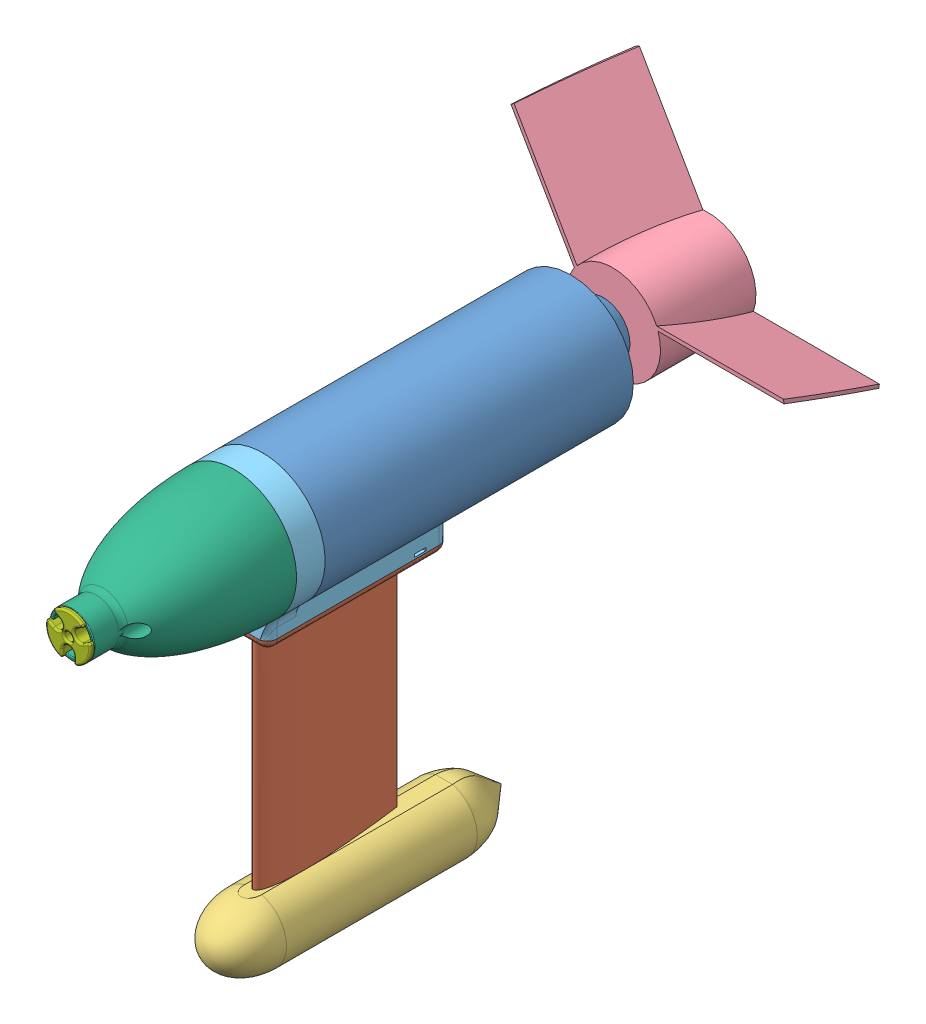
SolidWorks assembly reverse cat assembly, configuration Default. Lengths in mm.
Overall size (143.38 280.15 343.66).
7 component instances, 7 part files, 22 mates.
Components (placement in the parent):
- Flipsky 65161 Motor-2: Flipsky 65161 Motor [Default] at (22.7291 38 -117.7677) x (0.707107 0.707107 0) z (0 0 -1) size (65.5 65.5 241.5)
- mast - naca 0012-1: mast - naca 0012 [Default] at (22.7291 -62.5 -32.0177) x (0 0 -1) z (-1 0 0) size (95.94 125 35)
- bulb-1: bulb [Default] at (22.7291 -141.9115 -82.0177) size (35.27 35.28 155)
- prop-1: prop [Default] at (22.7291 38 -220.5177) x (1 0 0) z (0 1 0) size (143.38 50 164.92)
- reverse cat-2: reverse cat [Default] at (22.7291 38 -29.5177) x (-1 0 0) z (0 -1 0) size (65.5 95 71.11)
- nose cone-1: nose cone [Default] at (22.7291 38 -22.0177) x (0 0 1) z (-1 0 0) size (85 69.42 68.43)
- nose plug-1: nose plug [Default] at (22.7291 38 64.9823) x (1 0 0) z (0 1 0) size (23.52 14.81 22.73)
Mates (geometry in assembly coordinates):
- Coincident1: coincident: plane of ? through (-60605.8469 -37519.4359 -15) normal (0 0 -1); plane of Flipsky 65161 Motor-2 through (-28.2165 86.462 -15) normal (0 0 1)
- Coincident2: coincident: plane of mast - naca 0012-1 through (22.924 -125 -32.0449) normal (0 -1 0); plane of bulb-1 through (18.2291 -125 -132.0177) normal (0 1 0)
- Concentric4: concentric: circle of bulb-1; circle of mast - naca 0012-1
- Distance1: distance = 8 mm: plane of Flipsky 65161 Motor-2 through (22.7291 38 -278.5177) normal (0 0 -1); plane of prop-1 through (22.7291 38 -270.5177) normal (0 0 -1)
- Concentric6: concentric: circle of Flipsky 65161 Motor-2; circle of prop-1
- Coincident4: coincident: plane of ? through (-60605.8469 -37519.4359 0) normal (0 0 1); plane of assembly through (0 0 0) normal (0 0 1)
- Concentric11: concentric: circle of bulb-1; circle of mast - naca 0012-1
- Coincident7: coincident: plane of Flipsky 65161 Motor-2 through (22.7291 38 -37.0177) normal (0 0 1); plane of reverse cat-2 through (22.7291 38 -37.0177) normal (0 0 -1)
- Concentric12: concentric: circle of Flipsky 65161 Motor-2; circle of reverse cat-2
- Coincident8: coincident: plane of mast - naca 0012-1 through (22.924 0 -32.0449) normal (0 1 0); plane of reverse cat-2 through (10.2291 0 -27.0177) normal (0 -1 0)
- Concentric13: concentric: circle of mast - naca 0012-1; circle of reverse cat-2
- Concentric14: concentric: circle of mast - naca 0012-1; circle of reverse cat-2
- Concentric15: concentric: circle of Flipsky 65161 Motor-2; circle of reverse cat-2
- Coincident9: coincident: plane of mast - naca 0012-1; plane of ? through (-45.4365 115.7929 -99.0874) normal (0 1 0)
- Concentric16: concentric: circle of mast - naca 0012-1; circle of ?
- Concentric17: concentric: circle of mast - naca 0012-1; circle of ?
- Coincident11: coincident: plane of reverse cat-2 through (22.7291 38 -22.0177) normal (0 0 1); plane of nose cone-1 through (22.7291 70.75 -22.0177) normal (0 0 -1)
- Concentric20: concentric: circle of nose cone-1; circle of reverse cat-2
- Concentric21: concentric: circle of nose cone-1; circle of reverse cat-2
- Coincident12: coincident: plane of reverse cat-2 through (10.2291 0 -27.0177) normal (0 -1 0); plane of assembly through (0 0 0) normal (0 1 0)
- Coincident13: coincident: plane of nose cone-1 through (22.7291 38 62.9823) normal (0 0 1); plane of nose plug-1 through (22.7291 38 62.9823) normal (0 0 -1)
- Concentric22: concentric: circle of nose plug-1; circle of nose cone-1
